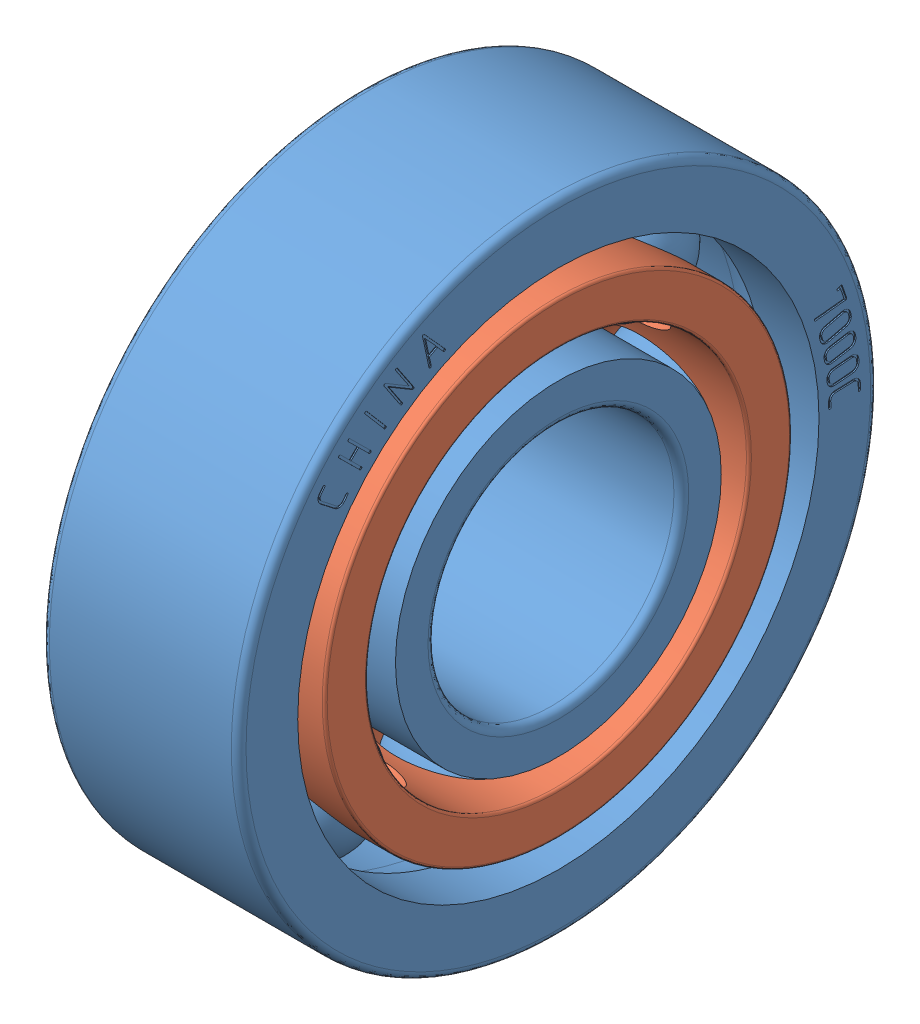
SolidWorks assembly 7000C, configuration По умолчанию. Lengths in mm.
Overall size (8 26 26).
2 component instances, 2 part files, 2 mates.
Components (placement in the parent):
- 7000-C-1: 7000-C [По умолчанию] at origin size (8 26 26)
- Сепаратор-1: Сепаратор [По умолчанию] at (-1.5224 0.5931 0.9295) x (0 0 -1) z (1 0 0) size (19 19 8)
Mates (geometry in assembly coordinates):
- Концентричный1: concentric aligned: cylinder of 7000-C-1 through (-22.1599 0.5931 0.9295) axis (1 0 0) radius 10.6; cylinder of Сепаратор-1 through (-5.5224 0.5931 0.9295) axis (1 0 0) radius 9.5
- Концентричный2: concentric: sphere of 7000-C-1; cylinder of Сепаратор-1 through (-1.5224 10.0941 10.4305) axis (0 -0.707107 -0.707107) radius 2.6
